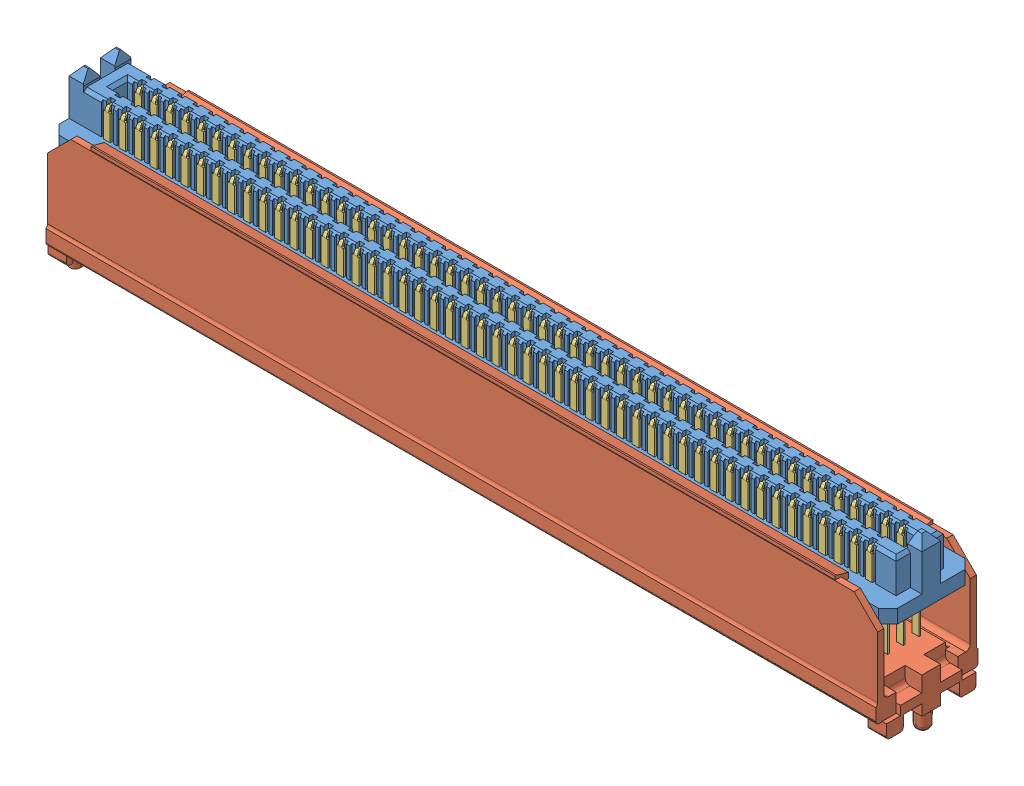
SolidWorks assembly Assem5, configuration Default. Lengths in mm.
Overall size (68.48 13.87 8.33).
6 component instances, 5 part files, 3 mates.
Components (placement in the parent):
- SEAM_50_09_0_L_04_2_A_K_TR-1: SEAM_50_09_0_L_04_2_A_K_TR [Default] at (0 8.89 0) size (68.48 13.87 8.33)
  - _SEAM_50_09_0_L_04_1_A_K_TR_body_2-1: _SEAM_50_09_0_L_04_1_A_K_TR_body_2 [Default] at origin size (68.48 6.35 7.06)
  - _SEAM_50_09_0_L_04_1_A_K_TR_spacer_4-1: _SEAM_50_09_0_L_04_1_A_K_TR_spacer_4 [Default] at origin size (68.48 11.13 8.33)
  - _SEAM_50_09_0_L_04_1_A_K_TR_conn_6-1: _SEAM_50_09_0_L_04_1_A_K_TR_conn_6 [Default] at origin size (67.97 11.29 6.55)
  - _SEAM_K_Pad_04_8-1: _SEAM_K_Pad_04_8 [Default] at (0 2.6924 0) size (5.99 0.13 5.99) (hidden)
  - _SEAM_Triangle_10-1: _SEAM_Triangle_10 [Default] at (32.2834 1.2954 -1.6764) x (-1 0 0) z (0 0 -1) size (1.02 1.27 0.13)
Mates (geometry in assembly coordinates):
- Coincident1: coincident: plane of ? through (32.7152 0 3.4036) normal (0 -1 0)
- Coincident2: coincident: plane of ? through (0 8.89 0) normal (0 0 1)
- Coincident3: coincident: plane of ? through (0 8.89 0) normal (1 0 0)
